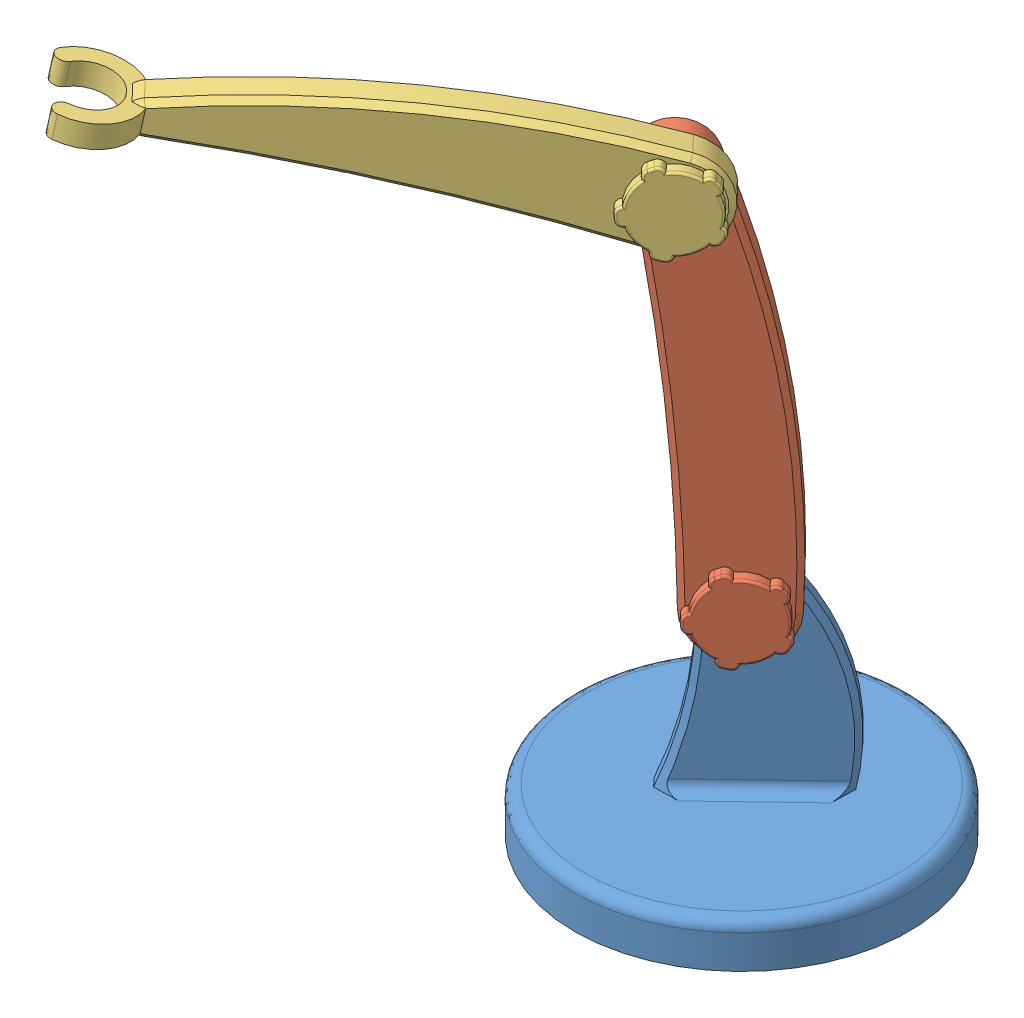
SolidWorks assembly two_link_Robotic_Arm_Assembly, configuration Predeterminado. Lengths in mm.
Overall size (262.1 327.25 294.49).
3 component instances, 3 part files, 4 mates.
Components (placement in the parent):
- Part1-1: Part1 [Predeterminado] at (-78.0418 0 198.8929) x (-0.723007 0 0.69084) z (-0.69084 0 -0.723007) size (150 115 150)
- Part2-1: Part2 [Predeterminado] at (-76.8998 184.3657 215.0906) x (-0.088159 0.992538 0.084237) z (0.69084 0 0.723007) size (205 46.12 30.09)
- Part3-1: Part3 [Predeterminado] at (-134.5165 283.773 290.8905) x (-0.711597 0.176959 0.679937) z (0.69084 0 0.723007) size (221.29 43.27 41.34)
Mates (geometry in assembly coordinates):
- Coincident2: coincident anti-aligned: plane of Part1-1 through (-119.0372 41.3028 244.9799) normal (0.69084 0 0.723007); plane of Part2-1 through (-82.0811 184.3657 209.668) normal (-0.69084 0 -0.723007)
- Concentric1: concentric aligned: circle of Part1-1; cylinder of Part2-1 through (-81.496 100 195.2778) axis (0.69084 0 0.723007) radius 5
- Coincident3: coincident anti-aligned: plane of Part2-1 through (-71.7185 184.3657 220.5131) normal (0.69084 0 0.723007); plane of Part3-1 through (-139.6978 283.773 285.468) normal (-0.69084 0 -0.723007)
- Concentric2: concentric aligned: circle of Part2-1; cylinder of Part3-1 through (-86.1204 268.7315 220.4432) axis (0.69084 0 0.723007) radius 5
